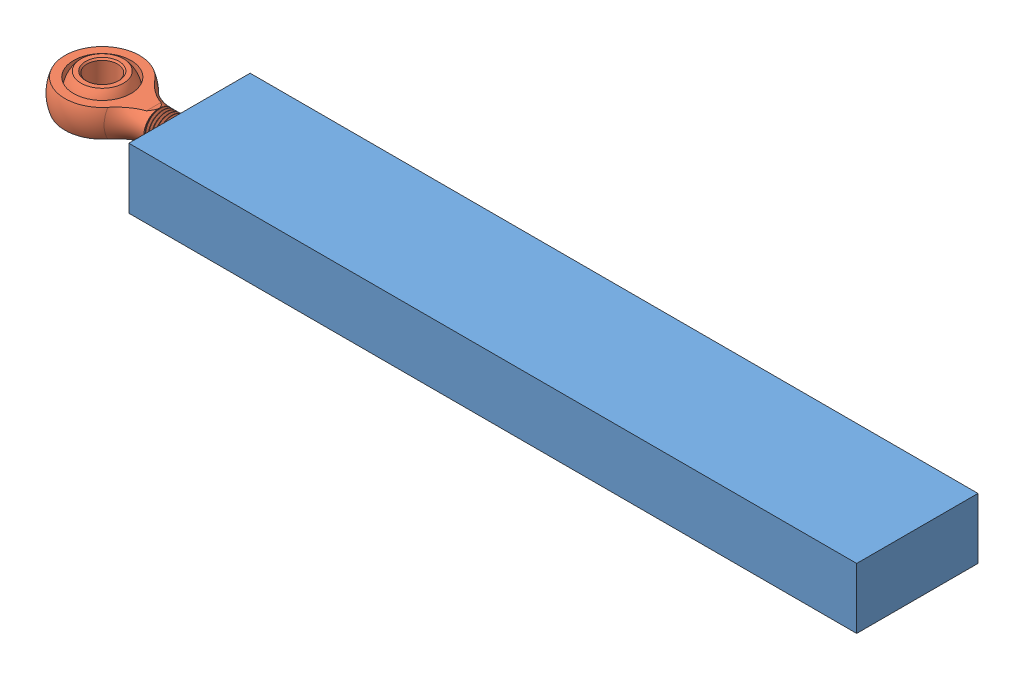
SolidWorks assembly Assem2, configuration Default. Lengths in mm.
Overall size (357.98 25.4 50.8).
2 component instances, 2 part files, 2 mates.
Components (placement in the parent):
- 1x2TubeStock-1: 1x2TubeStock [Default] at (73.3248 122.4546 244.6357) size (304.8 25.4 50.8)
- 60645K161-1: 60645K161 [60645K161] at (-24.733 135.1546 236.169) x (0 0 -1) z (0 1 0) size (33.34 78.84 15.88)
Mates (geometry in assembly coordinates):
- Parallel1: parallel aligned: plane of 1x2TubeStock-1 through (73.3248 122.4546 244.6357) normal (0 -1 0); plane of 60645K161-1 through (-65.2143 129.3999 252.8378) normal (0 -1 0)
- Parallel2: parallel aligned: plane of 1x2TubeStock-1 through (73.3248 147.8546 244.6357) normal (0 1 0); plane of 60645K161-1 through (-65.2143 140.9093 252.8378) normal (0 1 0)
